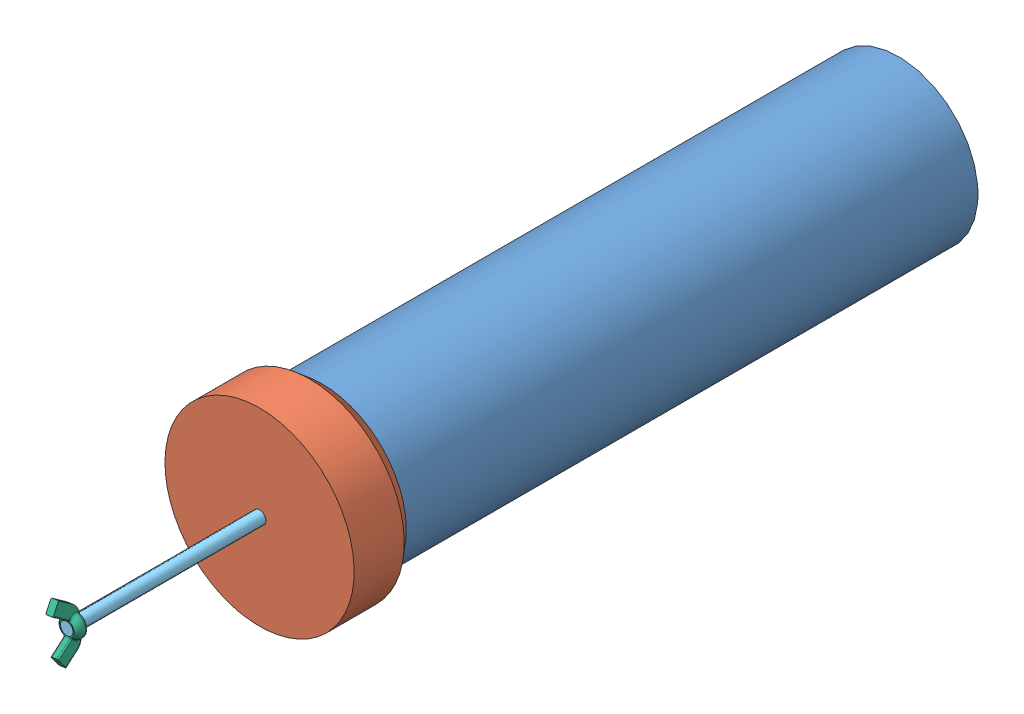
SolidWorks assembly Pipe ASSY, configuration Default. Lengths in mm.
Overall size (90.54 90.54 337.95).
8 component instances, 7 part files, 7 mates.
Components (placement in the parent):
- PVC Pipe-1: PVC Pipe [Default] at (75.9174 231.4685 7.4574) size (63.5 63.5 250)
- PVC End Cap-1: PVC End Cap [Default] at (75.9174 231.4685 262.4574) x (-0.974419 0.22474 0) z (-0.22474 -0.974419 0) size (75.5 25 75.5)
- Comp Spring-1: Comp Spring [Default] at (75.9174 231.4685 257.4574) x (-0.327006 0.945022 0) z (-0.945022 -0.327006 0) size (28.51 113.99 27.95)
- Plunger ASSY-1: Plunger ASSY [Default] at (45.8129 232.6674 156.515) x (0.035729 -0.999362 0) z (0 0 1) size (26 26 196)
  - Plunger Head-1: Plunger Head [Default] at (2.2737 30.0425 32.8918) size (26 26 40)
  - M5 Rod-1: M5 Rod [Default] at (2.2737 30.0425 32.8918) x (0 0 1) z (0.999135 -0.041577 0) size (150 5 5)
  - Wing Nut M5-1: Wing Nut M5 [По умолчанию] at (2.2737 30.0425 178.8918) x (0.994256 0.107027 0) z (0.107027 -0.994256 0) size (22 10.07 9)
  - Thread Sleeve-1: Thread Sleeve [Default] at (2.2737 30.0425 55.3918) x (0.404445 -0.914562 0) z (0 0 -1) size (12 12 45)
Mates (geometry in assembly coordinates):
- Concentric1: concentric anti-aligned: cylinder of PVC Pipe-1 through (75.9174 231.4685 257.4574) axis (0 0 -1) radius 31.75; cylinder of PVC End Cap-1 through (75.9174 231.4685 237.4574) axis (0 0 1) radius 31.7505
- Coincident1: coincident anti-aligned: plane of PVC Pipe-1 through (75.9174 231.4685 257.4574) normal (0 0 1); plane of PVC End Cap-1 through (75.9174 231.4685 257.4574) normal (0 0 -1)
- Coincident3: coincident aligned: plane of PVC End Cap-1 through (75.9174 231.4685 257.4574) normal (0 0 -1); plane of Comp Spring-1 through (75.9174 231.4685 257.4574) normal (0 0 -1)
- Concentric2: concentric anti-aligned: cylinder of PVC Pipe-1 through (75.9174 231.4685 257.4574) axis (0 0 -1) radius 20.6; line of Comp Spring-1 through (75.9174 231.4685 147.4574) axis (0 0 1)
- Concentric4: concentric anti-aligned: cylinder of PVC End Cap-1 through (75.9174 231.4685 237.4574) axis (0 0 1) radius 2.55; cylinder of Plunger ASSY-1/M5 Rod-1 through (75.9174 231.4685 339.4068) axis (0 0 -1) radius 2.5
- Concentric6: concentric anti-aligned: cylinder of PVC Pipe-1 through (75.9174 231.4685 257.4574) axis (0 0 -1) radius 20.6; cylinder of Plunger ASSY-1/Plunger Head-1 through (75.9174 231.4685 189.4068) axis (0 0 1) radius 3
- LimitDistance2: limit distance = 72.9494 mm anti-aligned: plane of PVC End Cap-1 through (75.9174 231.4685 262.4574) normal (0 0 1); plane of Plunger ASSY-1/Wing Nut M5-1 through (75.9174 231.4685 335.4068) normal (0 0 -1)
